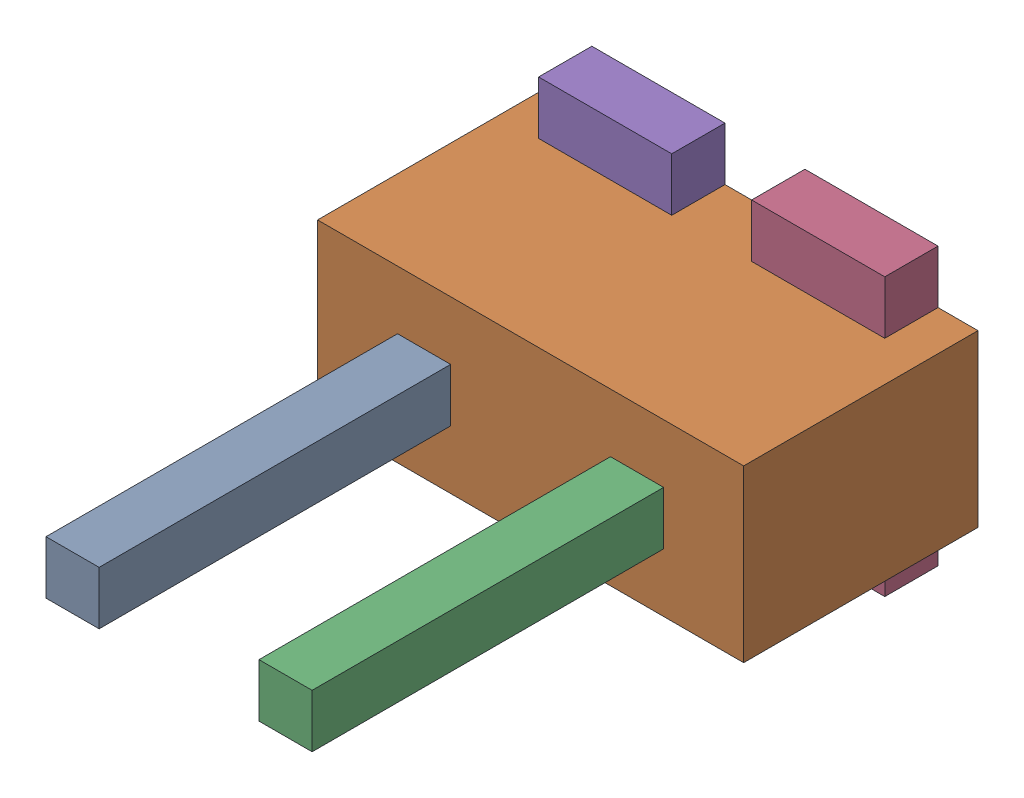
SolidWorks assembly J16, configuration ﾃﾞﾌｫﾙﾄ. Lengths in mm.
Overall size (4 2.6 5.5).
10 component instances, 3 part files, 0 mates.
Components (placement in the parent):
- 689260424-1: 689260424 [ﾃﾞﾌｫﾙﾄ] at (5.4999 60.75 2.2) size (0.5 0.5 3.3)
  - Extruded_23-1: Extruded_23 [ﾃﾞﾌｫﾙﾄ] at origin size (0.5 0.5 3.3)
- 689260560-1: 689260560 [ﾃﾞﾌｫﾙﾄ] at (6.5 60.75 0) size (4 1.6 2.2)
  - Extruded_24-1: Extruded_24 [ﾃﾞﾌｫﾙﾄ] at origin size (4 1.6 2.2)
- 689260424-2: 689260424 [ﾃﾞﾌｫﾙﾄ] at (7.4994 60.75 2.2) size (0.5 0.5 3.3)
  - Extruded_23-1: Extruded_23 [ﾃﾞﾌｫﾙﾄ] at origin size (0.5 0.5 3.3)
- 689260696-1: 689260696 [ﾃﾞﾌｫﾙﾄ] at (7.4999 60.7499 0) size (1.25 2.6 0.5)
  - Extruded_25-1: Extruded_25 [ﾃﾞﾌｫﾙﾄ] at origin size (1.25 2.6 0.5)
- 689260696-2: 689260696 [ﾃﾞﾌｫﾙﾄ] at (5.4999 60.7499 0) size (1.25 2.6 0.5)
  - Extruded_25-1: Extruded_25 [ﾃﾞﾌｫﾙﾄ] at origin size (1.25 2.6 0.5)
